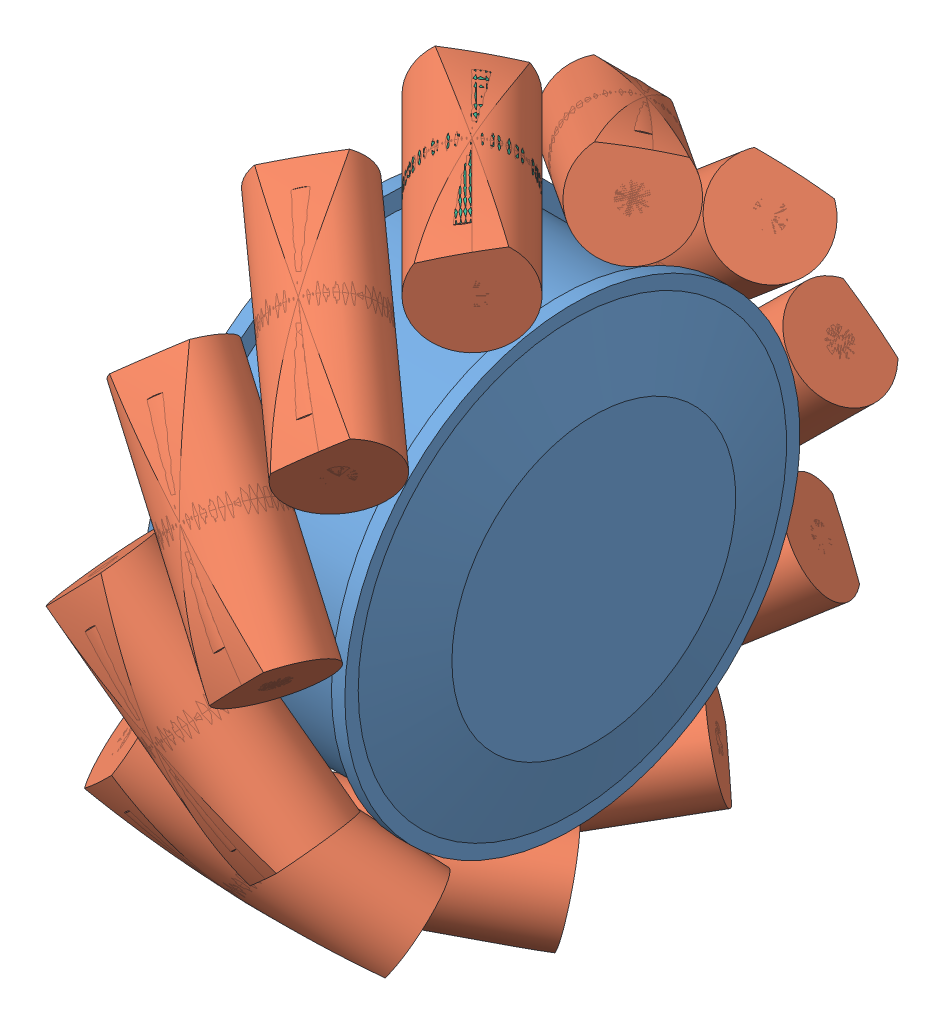
SolidWorks assembly Прототип колеса, configuration 00. Lengths in mm.
Overall size (133.08 255.64 256.18).
21 component instances, 8 part files, 9 mates.
Components (placement in the parent):
- Мотор-колесо ZLLG80ASM800 (мотор)-1: Мотор-колесо ZLLG80ASM800 (мотор) [1 крепление] at origin size (133 170 170)
- Боченок габарит-1: Боченок габарит [--] at (0 101.5 0) x (0.707107 0 -0.707107) z (0.707107 0 0.707107) size (37 37 91.92)
- Боченок габарит-2: Боченок габарит [--] at (0 85.3872 54.875) x (0.707107 0.382291 -0.594856) z (0.707107 -0.382291 0.594856) size (37 37 91.92)
- Боченок габарит-3: Боченок габарит [--] at (0 42.1646 92.3276) x (0.707107 0.643207 -0.293743) z (0.707107 -0.643207 0.293743) size (37 37 91.92)
- Боченок габарит-4: Боченок габарит [--] at (0 -14.445 100.4669) x (0.707107 0.699909 0.100632) z (0.707107 -0.699909 -0.100632) size (37 37 91.92)
- Боченок габарит-5: Боченок габарит [--] at (0 -66.4684 76.7086) x (0.707107 0.534396 0.463056) z (0.707107 -0.534396 -0.463056) size (37 37 91.92)
- Боченок габарит-6: Боченок габарит [--] at (0 -97.3885 28.5959) x (0.707107 0.199215 0.678464) z (0.707107 -0.199215 -0.678464) size (37 37 91.92)
- Боченок габарит-7: Боченок габарит [--] at (0 -97.3885 -28.5959) x (0.707107 -0.199215 0.678464) z (0.707107 0.199215 -0.678464) size (37 37 91.92)
- Боченок габарит-8: Боченок габарит [--] at (0 -66.4684 -76.7086) x (0.707107 -0.534396 0.463056) z (0.707107 0.534396 -0.463056) size (37 37 91.92)
- Боченок габарит-9: Боченок габарит [--] at (0 -14.445 -100.4669) x (0.707107 -0.699909 0.100632) z (0.707107 0.699909 -0.100632) size (37 37 91.92)
- Боченок габарит-10: Боченок габарит [--] at (0 42.1646 -92.3276) x (0.707107 -0.643207 -0.293743) z (0.707107 0.643207 0.293743) size (37 37 91.92)
- Боченок габарит-11: Боченок габарит [--] at (0 85.3872 -54.875) x (0.707107 -0.382291 -0.594856) z (0.707107 0.382291 0.594856) size (37 37 91.92)
- Ролик диагональный-1: Ролик диагональный [00] at (0 101.5 0) x (-0.511229 -0.690862 0.511229) z (-0.707107 0 -0.707107) size (37 37 69.98)
  - Боченок габарит-1: Боченок габарит [--] at origin size (37 37 91.92) (hidden)
  - Подшипник 6100-1: Подшипник 6100 [--] at (0 0 30.99) x (0 0 1) z (0.161819 -0.986821 0) size (8 26 26)
  - Ступица-1: Ступица [--] at origin size (30 30 69.98)
  - Ось-1: Ось [--] at origin size (14 14 53.98)
  - Подшипник 6100-2: Подшипник 6100 [--] at (0 0 -30.99) x (0 0 -1) z (-0.273874 0.961766 0) size (8 26 26)
  - Покрышка-1: Покрышка [--] at origin size (37 37 69.98)
- Фланец колеса-1: Фланец колеса [--] at (-37.5 0 0) x (0 0 -1) z (1 0 0) size (230 230 22.27) (hidden)
- Винты с цилиндрической головкой (ГОСТ 11738-84)-1: Винты с цилиндрической головкой (ГОСТ 11738-84) [Винт М10-(6g)x35 ГОСТ 11738-84] at (-31.1056 101.5 -31.1056) x (-0.511229 -0.690862 0.511229) z (-0.707107 0 -0.707107) size (16 16 45.28) (hidden)
Mates (geometry in assembly coordinates):
- Совпадение1: coincident: plane of Боченок габарит-1 through (0 101.5 0) normal (0.707107 0 0.707107); plane of assembly through (0 0 0) normal (-0.707107 0 -0.707107)
- Совпадение2: coincident: plane of Боченок габарит-1 through (0 101.5 0) normal (0.707107 0 -0.707107); plane of assembly through (0 0 0) normal (0.707107 0 -0.707107)
- Совпадение3: coincident: point of Боченок габарит-1; point of assembly
- Совпадение4: coincident: circle of Боченок габарит-1; circle of Ролик диагональный-1/Покрышка-1
- Совпадение5: coincident: plane of Мотор-колесо ZLLG80ASM800 (мотор)-1 through (-37.5 85 0) normal (-1 0 0); plane of Фланец колеса-1 through (-37.5 0 0) normal (1 0 0)
- Совпадение6: coincident: plane of Фланец колеса-1 through (-37.5 0 0) normal (0 1 0); plane of assembly through (0 0 0) normal (0 1 0)
- Совпадение7: coincident: plane of Фланец колеса-1 through (-37.5 0 0) normal (0 0 -1); plane of assembly through (0 0 0) normal (0 0 1)
- Концентричный2: concentric: cylinder of Винты с цилиндрической головкой (ГОСТ 11738-84)-1 through (-6.3569 101.5 -6.3569) axis (0.707107 0 0.707107) radius 5; cylinder of Ролик диагональный-1/Подшипник 6100-1 through (685.1935 101.5 685.1935) axis (0.707107 0 0.707107) radius 12
- Расстояние1: distance = 9 mm: plane of Винты с цилиндрической головкой (ГОСТ 11738-84)-1 through (-33.8413 105.5487 -28.37) normal (0.707107 0 0.707107); plane of Ролик диагональный-1/Подшипник 6100-1 through (-17.3307 108.6725 -32.1527) normal (-0.707107 0 -0.707107)
